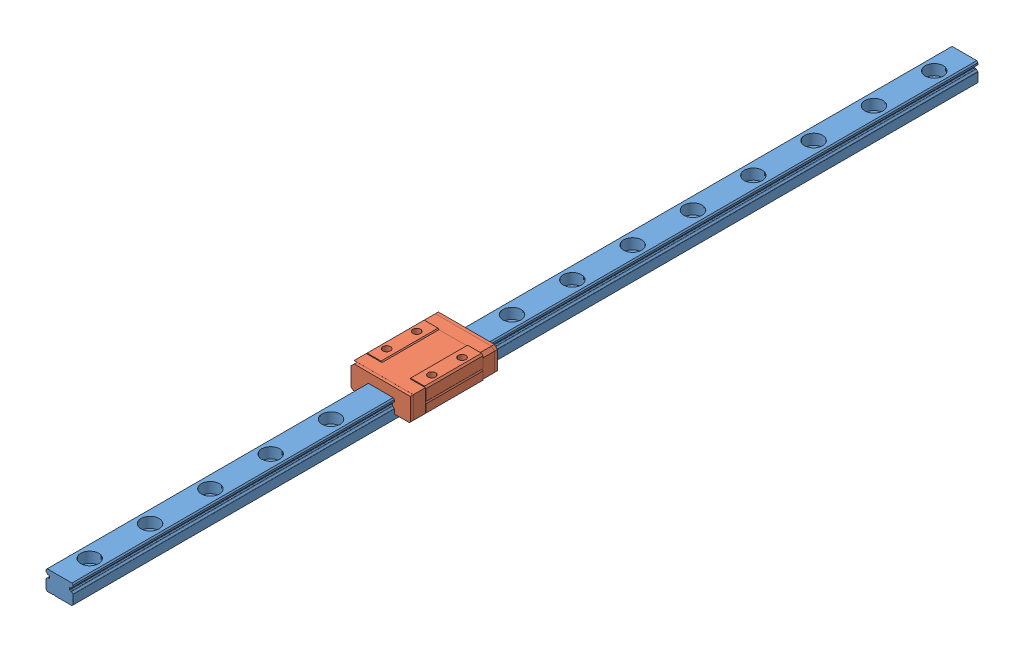
SolidWorks assembly X Rail, configuration Default. Lengths in mm.
Overall size (25.38 12.6 300).
3 component instances, 3 part files, 6 mates.
Components (placement in the parent):
- MGN9-300MM-1: MGN9-300MM [Default] at (68.4102 185.8946 388.0774) size (9 6.6 300)
- MGN9-1: MGN9 [Default] at (68.4102 185.8946 264.6487) size (20 8.05 28.9)
- X Carriage-1: X Carriage [Default] at (68.4102 189.3946 264.6487) x (1 0 0) z (0 1 0) size (25.38 28.9 12.5)
Mates (geometry in assembly coordinates):
- Coincident1: coincident anti-aligned: plane of MGN9-300MM-1 through (72.5102 185.8946 88.0774) normal (0 1 0); plane of MGN9-1 through (72.9102 185.8946 250.1987) normal (0 -1 0)
- Coincident2: coincident anti-aligned: plane of MGN9-300MM-1 through (63.9102 185.4946 88.0774) normal (-1 0 0); plane of MGN9-1 through (63.9102 182.9407 250.1987) normal (1 0 0)
- InPlace1: in place: plane of MGN9-1 through (68.4102 189.3946 264.6487) normal (0 1 0); plane of ? through (0 189.3946 0) normal (0 1 0); moOrthogonalPlaneRef_w of MGN9-1 through (68.4102 189.3946 264.6487) normal (0 1 0); plane of ? through (0 189.3946 0) normal (0 0 -1); plane of MGN9-1 through (68.4102 189.3946 264.6487) normal (0 1 0); line of ? through (-55 0 189.3946) axis (0 1 0); plane of MGN9-1 through (68.4102 189.3946 264.6487) normal (0 1 0); unknown of X Carriage-1
- Coincident3: coincident aligned: plane of MGN9-1; plane of X Carriage-1
- Coincident4: coincident aligned: moOrthogonalPlaneRef_w of MGN9-1 through (68.4102 189.3946 264.6487) normal (0 0 -1); plane of X Carriage-1 through (68.4102 189.3946 264.6487) normal (0 0 -1)
- Coincident5: coincident anti-aligned: moOrthogonalPlaneRef_w of MGN9-1 through (68.4102 189.3946 264.6487) normal (-1 0 0); plane of X Carriage-1
